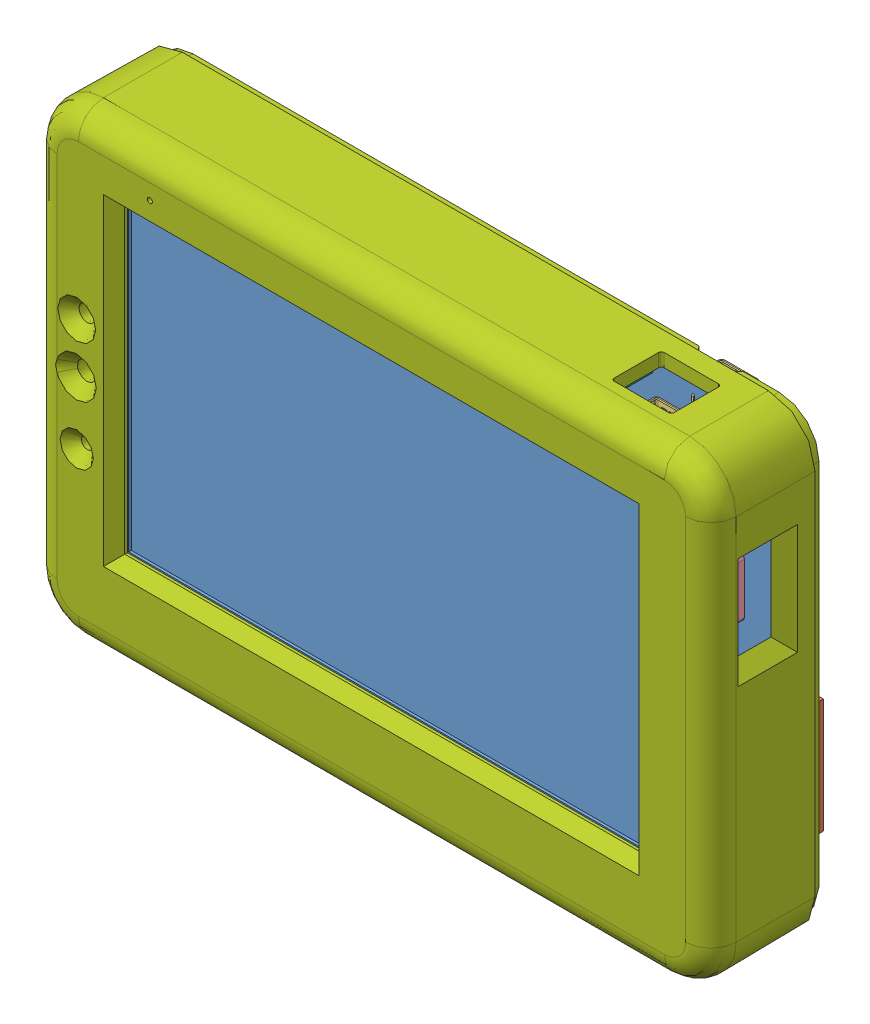
SolidWorks assembly Mikromedia Plus With Components, configuration 001. Lengths in mm.
Overall size (129.7 88.2 38.73).
10 component instances, 7 part files, 30 mates.
Components (placement in the parent):
- Mikromedia Plus Board-1: Mikromedia Plus Board [001] x (-1 0 0) z (0 0 -1) size (119.54 79.3 19.1)
- ethernet port-1: ethernet port [Default] at (-12.3927 -56.7792 -14.0239) x (-1 0 0) z (0 -1 0) size (16.99 18.27 21.84)
- USB-Mini-B-1: USB-Mini-B [Default] at (-10.8769 10.2972 -3.5875) x (1 0 0) z (0 1 0) size (7.7 5.76 9)
- USB-Mini-B-2: USB-Mini-B [Default] at (-10.8769 10.2972 -16.0239) x (1 0 0) z (0 1 0) size (7.7 5.76 9)
- micro-sd-card-1: micro-sd-card [Default] at (1.8157 -19.415 -1.5875) x (1 0 0) z (0 1 0) size (17.2 2.7 16.1)
- pin_header_aw140-eg-g26b-1: pin_header_aw140-eg-g26b [Default] at (-55.753 -65.532 -1.5875) x (1 0 0) z (0 -1 0) size (66.04 11.6 2.5)
- pin_header_aw140-eg-g26b-2: pin_header_aw140-eg-g26b [Default] at (-55.753 8.128 -1.5875) x (1 0 0) z (0 -1 0) size (66.04 11.6 2.5)
- Pin Header Socket 26 pin-1: Pin Header Socket 26 pin [Default] at (-89.003 6.878 -4.2364) x (1 0 0) z (0 -1 0) size (66.7 11.6 2.5)
- Pin Header Socket 26 pin-2: Pin Header Socket 26 pin [Default] at (-89.003 -66.782 -4.2364) x (1 0 0) z (0 -1 0) size (66.7 11.6 2.5)
- Mikromedia Plus Board case-1: Mikromedia Plus Board case [001] x (-1 0 0) z (0 0 -1) size (129.7 88.2 38.73)
Mates (geometry in assembly coordinates):
- Coincident1: coincident anti-aligned: plane of Mikromedia Plus Board-1 through (0 0 0) normal (0 0 -1); plane of assembly through (0 0 0) normal (0 0 1)
- Coincident2: coincident anti-aligned: plane of Mikromedia Plus Board-1 through (0 0 0) normal (-1 0 0); plane of assembly through (0 0 0) normal (1 0 0)
- Coincident3: coincident aligned: plane of Mikromedia Plus Board-1; plane of assembly through (0 0 0) normal (0 1 0)
- Coincident4: coincident anti-aligned: plane of Mikromedia Plus Board-1 through (2.7457 -2.159 -1.5875) normal (0 0 -1); plane of USB-Mini-B-1 through (-7.0269 7.5472 -1.5875) normal (0 0 1)
- Coincident5: coincident aligned: plane of Mikromedia Plus Board-1 through (-15.7582 10.2972 -1.5875) normal (0 1 0); plane of USB-Mini-B-1 through (-10.8769 10.2972 -3.5875) normal (0 1 0)
- Coincident6: coincident: line of Mikromedia Plus Board-1 through (-14.7269 3.429 0) axis (0 1 0); plane of USB-Mini-B-1 through (-14.7269 10.2972 -4.0409) normal (-1 0 0)
- Coincident7: coincident anti-aligned: plane of Mikromedia Plus Board-1 through (2.7457 -2.159 -14.0239) normal (0 0 -1); plane of USB-Mini-B-2 through (-7.0269 7.5472 -14.0239) normal (0 0 1)
- Coincident8: coincident aligned: plane of USB-Mini-B-1 through (-10.8769 10.2972 -3.5875) normal (0 1 0); plane of USB-Mini-B-2 through (-10.8769 10.2972 -16.0239) normal (0 1 0)
- Coincident9: coincident aligned: plane of USB-Mini-B-1 through (-14.7269 10.2972 -4.0409) normal (-1 0 0); plane of USB-Mini-B-2 through (-14.7269 10.2972 -16.4773) normal (-1 0 0)
- Coincident10: coincident anti-aligned: plane of Mikromedia Plus Board-1 through (2.7457 -2.159 -1.5875) normal (0 0 -1); plane of micro-sd-card-1 through (-5.664 -12.0718 -1.5875) normal (0 0 1)
- Coincident11: coincident aligned: plane of Mikromedia Plus Board-1 through (4.0157 -63.8912 -1.5875) normal (1 0 0); plane of micro-sd-card-1 through (4.0157 -11.215 -2.9375) normal (1 0 0)
- Width2: width anti-aligned: plane of micro-sd-card-1 through (1.8157 -19.415 -1.5875) normal (0 -1 0); plane of micro-sd-card-1 through (-12.6843 -4.715 -1.5875) normal (0 1 0); plane of Mikromedia Plus Board-1 through (2.7457 -20.701 -1.5875) normal (0 1 0); plane of Mikromedia Plus Board-1 through (2.7457 -3.429 -1.5875) normal (0 -1 0)
- Coincident12: coincident anti-aligned: plane of Mikromedia Plus Board-1 through (2.7457 -2.159 -14.0239) normal (0 0 -1); plane of ethernet port-1 through (-20.0127 -45.8572 -14.0239) normal (0 0 1)
- Coincident13: coincident aligned: plane of Mikromedia Plus Board-1 through (0.2057 -67.7012 -14.0239) normal (0 -1 0); plane of ethernet port-1 through (-4.7727 -67.7012 -27.4859) normal (0 -1 0)
- Distance1: distance = 8.7884 mm aligned: plane of ethernet port-1 through (-4.7727 -67.7012 -27.4859) normal (1 0 0); plane of Mikromedia Plus Board-1 through (4.0157 -63.8912 -14.0239) normal (1 0 0)
- Concentric1: concentric aligned: cylinder of Mikromedia Plus Board-1 through (-87.503 -65.532 -1.5875) axis (0 0 1) radius 0.9271; circle of pin_header_aw140-eg-g26b-1
- Coincident15: coincident anti-aligned: plane of Mikromedia Plus Board-1 through (2.7457 -2.159 -1.5875) normal (0 0 -1); plane of pin_header_aw140-eg-g26b-1 through (-87.403 -63.0355 -1.5875) normal (0 0 1)
- Parallel1: parallel aligned: plane of Mikromedia Plus Board-1 through (0.2057 -67.7012 -1.5875) normal (0 -1 0); plane of pin_header_aw140-eg-g26b-1 through (-88.3685 -66.7847 -4.1275) normal (0 -1 0)
- Concentric2: concentric aligned: cylinder of Mikromedia Plus Board-1 through (-87.503 8.128 -1.5875) axis (0 0 1) radius 0.9271; circle of pin_header_aw140-eg-g26b-2
- Coincident16: coincident anti-aligned: plane of Mikromedia Plus Board-1 through (2.7457 -2.159 -1.5875) normal (0 0 -1); plane of pin_header_aw140-eg-g26b-2 through (-87.403 10.6245 -1.5875) normal (0 0 1)
- Parallel2: parallel aligned: plane of Mikromedia Plus Board-1 through (-15.7582 10.2972 -1.5875) normal (0 1 0); plane of pin_header_aw140-eg-g26b-2 through (-86.4375 9.3738 -4.1275) normal (0 1 0)
- Concentric3: concentric anti-aligned: cylinder of Mikromedia Plus Board-1 through (-87.503 -65.532 -14.0239) axis (0 0 1) radius 0.9271; circle of Pin Header Socket 26 pin-2
- Coincident17: coincident anti-aligned: plane of Mikromedia Plus Board-1 through (2.7457 -2.159 -12.4364) normal (0 0 1); plane of Pin Header Socket 26 pin-2 through (-89.003 -64.282 -12.4364) normal (0 0 -1)
- Parallel3: parallel aligned: plane of Mikromedia Plus Board-1 through (0.2057 -67.7012 -14.0239) normal (0 -1 0); plane of Pin Header Socket 26 pin-2 through (-89.003 -66.782 -12.4364) normal (0 -1 0)
- Concentric4: concentric anti-aligned: cylinder of Mikromedia Plus Board-1 through (-87.503 8.128 -14.0239) axis (0 0 1) radius 0.9271; circle of Pin Header Socket 26 pin-1
- Coincident18: coincident anti-aligned: plane of Mikromedia Plus Board-1 through (2.7457 -2.159 -12.4364) normal (0 0 1); plane of Pin Header Socket 26 pin-1 through (-89.003 9.378 -12.4364) normal (0 0 -1)
- Parallel4: parallel aligned: plane of Mikromedia Plus Board-1 through (-15.7582 10.2972 -14.0239) normal (0 1 0); plane of Pin Header Socket 26 pin-1 through (-89.003 9.378 -12.4364) normal (0 1 0)
- Coincident19: coincident aligned: plane of Mikromedia Plus Board-1 through (2.7457 -2.159 -14.0239) normal (0 0 -1); plane of Mikromedia Plus Board case-1 through (2.7457 -2.159 -14.0239) normal (0 0 -1)
- Coincident21: coincident aligned: plane of Mikromedia Plus Board-1 through (-3.1293 -62.3011 5.08) normal (0 -1 0); plane of Mikromedia Plus Board case-1 through (-3.1293 -62.3011 5.08) normal (0 -1 0)
- Coincident22: coincident aligned: plane of Mikromedia Plus Board-1 through (-3.1293 -62.3011 5.08) normal (1 0 0); plane of Mikromedia Plus Board case-1 through (-3.1293 -62.3011 5.08) normal (1 0 0)
